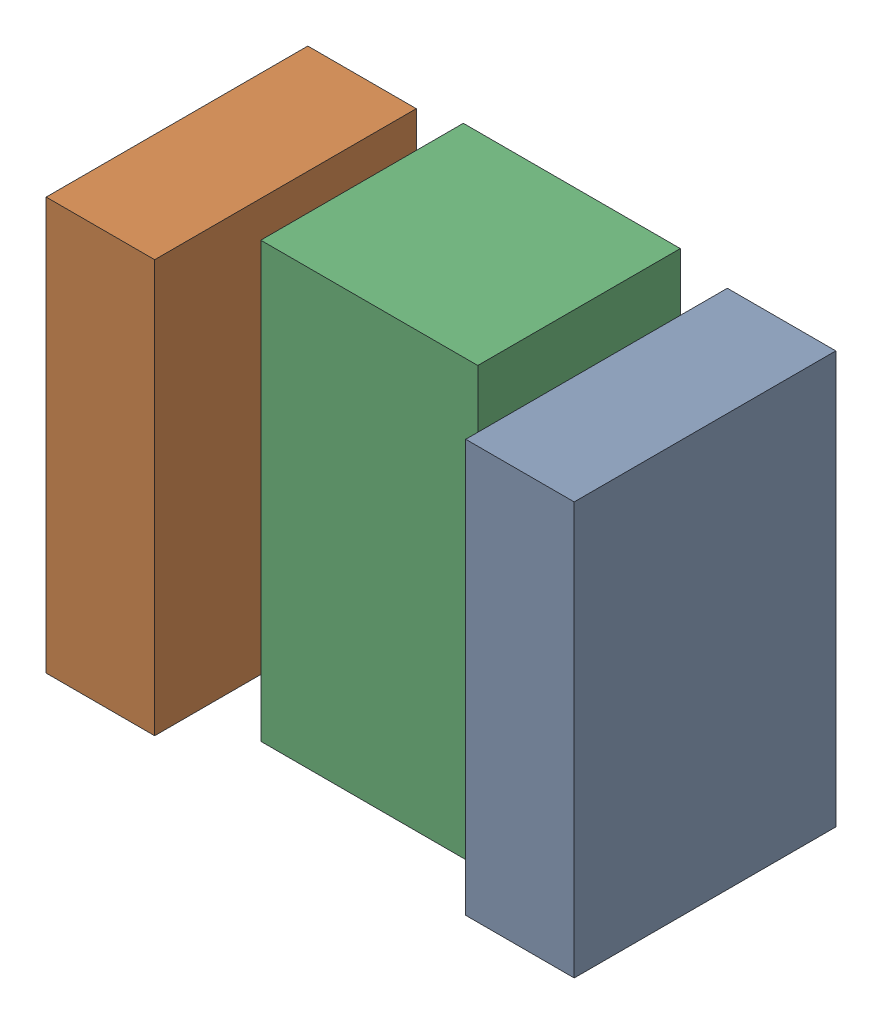
SolidWorks assembly C11_Motor_6Kanaloa_v2.0.0_Motor, configuration Default. Lengths in mm.
Overall size (3.65 3 1.81).
6 component instances, 2 part files, 0 mates.
Components (placement in the parent):
- 334788400-1: 334788400 [Default] at (36.248 135.636 0) size (0.75 2.85 1.81)
  - Extruded_5-1: Extruded_5 [Default] at origin size (0.75 2.85 1.81)
- 334788400-2: 334788400 [Default] at (33.348 135.636 0) size (0.75 2.85 1.81)
  - Extruded_5-1: Extruded_5 [Default] at origin size (0.75 2.85 1.81)
- 334788656-1: 334788656 [Default] at (34.798 135.636 0) size (1.5 3 1.4)
  - Extruded_1-1: Extruded_1 [Default] at origin size (1.5 3 1.4)
